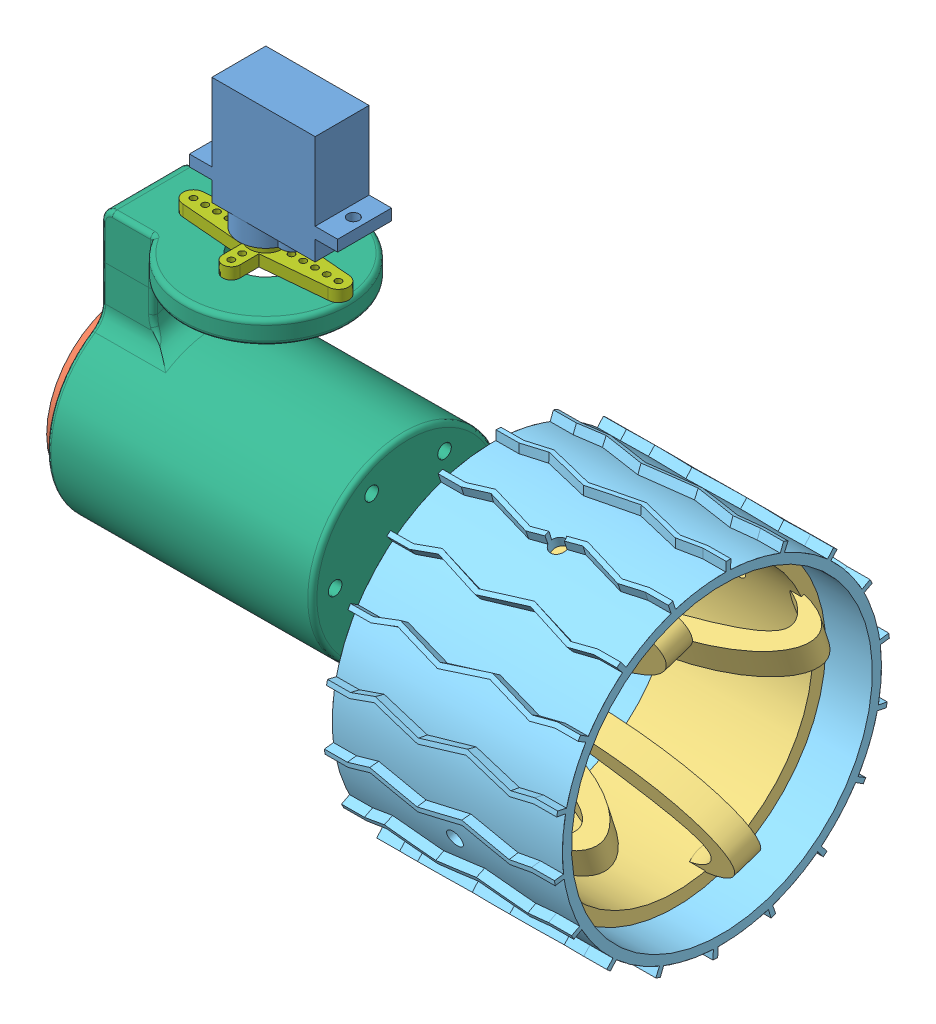
SolidWorks assembly Servo x Wheel Assembly, configuration Default. Lengths in mm.
Overall size (129.25 126.15 93.2).
8 component instances, 7 part files, 6 mates.
Components (placement in the parent):
- mg90s servo-1: mg90s servo [Default] at (-3.566 79.8877 -6.8981) x (0.999998 0 -0.001874) z (-0.001874 0 -0.999998) size (32.3 31.6 11.8)
- Motor x Wheel Assembly-1: Motor x Wheel Assembly [Default] at (45.6976 3.5404 -73.377) x (-0.004847 0 -0.999988) z (-0.999988 0 0.004847) size (92.57 92.9 128.8)
  - motor-1: motor [Default] at (-60.357 -3.1473 15.5878) size (37 37 78.8)
  - wheel inner-1: wheel inner [Default] at (-60.357 3.3527 -15.4122) x (0.952401 -0.304848 0) z (0.304848 0.952401 0) size (65.75 39.75 65.75)
  - wheel x motor connector test 2-1: wheel x motor connector test 2 [Default] at (-60.357 3.3527 9.5878) x (0.889009 0.457889 0) z (0 0 -1) size (25 25 25)
  - wheel outer-1: wheel outer [Default] at (-60.357 3.3527 -55.4122) x (-0.304848 -0.952401 0) z (0 0 1) size (74.01 73.51 50)
- servo x motor holder-1: servo x motor holder [Default] at (-15.6769 41.6877 -12.7219) x (0.999988 0 -0.004847) z (0.004847 0 0.999988) size (57.8 61 42)
- mg90s servo horn-1: mg90s servo horn [Default] at (20.3227 46.6877 -12.8964) x (-0.999988 0 0.004847) z (-0.004847 0 -0.999988) size (36 5 19)
Mates (geometry in assembly coordinates):
- Concentric1: concentric aligned: cylinder of mg90s servo-1 through (2.3229 48.2877 -12.8091) axis (0 1 0) radius 2.375; cylinder of mg90s servo horn-1 through (2.3229 48.2877 -12.8091) axis (0 1 0) radius 2.175
- Coincident1: coincident anti-aligned: plane of mg90s servo-1 through (2.3229 48.2877 -12.8091) normal (0 -1 0); plane of mg90s servo horn-1 through (2.3229 48.2877 -12.8091) normal (0 1 0)
- Coincident3: coincident aligned: circle of servo x motor holder-1; circle of mg90s servo horn-1
- Coincident8: coincident aligned: circle of servo x motor holder-1; circle of mg90s servo horn-1
- Coincident9: coincident anti-aligned: circle of Motor x Wheel Assembly-1/motor-1; circle of servo x motor holder-1
- Coincident10: coincident anti-aligned: circle of Motor x Wheel Assembly-1/motor-1; circle of servo x motor holder-1
